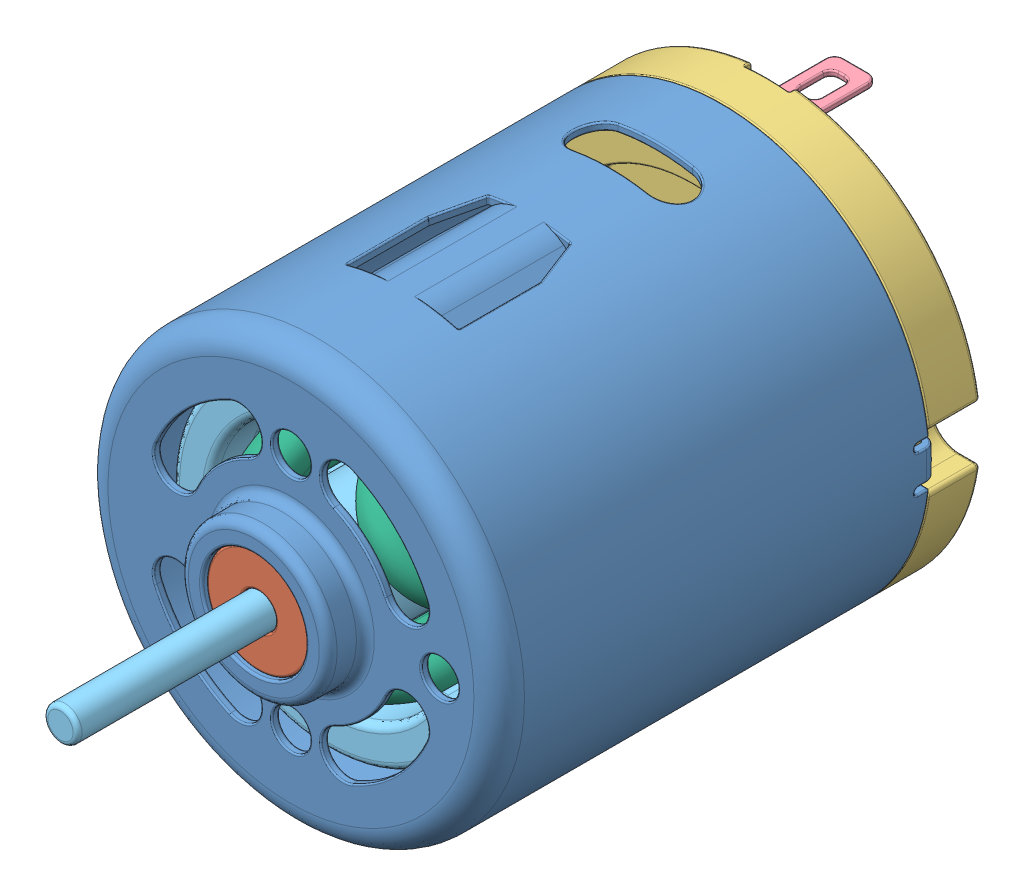
SolidWorks assembly DC Motor 12V, configuration Predeterminado. Lengths in mm.
Overall size (28.03 28 53.5).
9 component instances, 6 part files, 25 mates.
Components (placement in the parent):
- Carcaça12V-1: Carcaça12V [Predeterminado] at (0 0 24.0663) size (28.03 28 32.04)
- Bucha12V-1: Bucha12V [Predeterminado] at (0 0 26.0163) x (0.994754 0.102295 0) z (0 0 1) size (7 7 0.5)
- Mancal12V-1: Mancal12V [Predeterminado] at (0 0 -2.9337) x (-1 0 0) z (0 0 -1) size (27.69 28 8)
- Terminal12V-1: Terminal12V [Predeterminado] at (0 -11.5 -3.9337) x (1 0 0) z (0 1 0) size (2.9 10 0.4)
- Terminal12V-2: Terminal12V [Predeterminado] at (0 11.5 -3.9337) x (1 0 0) z (0 1 0) size (2.9 10 0.4)
- Eixo12V-1: Eixo12V [Predeterminado] at (0 0 39.5663) x (-0.33009 -0.943949 0) z (0 0 1) size (21 20.89 51)
- Enrolamento12V-1: Enrolamento12V [Predeterminado] at (-5.1702 1.808 12.5663) x (0.33009 0.943949 0) z (0 0 1) size (10 3 20)
- Enrolamento12V-2: Enrolamento12V [Predeterminado] at (1.0194 -5.3815 12.5663) x (-0.982529 -0.186108 0) z (0 0 1) size (10 3 20)
- Enrolamento12V-3: Enrolamento12V [Predeterminado] at (4.1509 3.5736 12.5663) x (0.652439 -0.757841 0) z (0 0 1) size (10 3 20)
Mates (geometry in assembly coordinates):
- Concentric1: concentric: cylinder of Carcaça12V-1 through (0 0 -4.9337) axis (0 0 1) radius 14; cylinder of Eixo12V-1 through (0 0 -11.4337) axis (0 0 1) radius 1.15
- Coincident1: coincident: plane of Carcaça12V-1 through (0 0 23.5663) normal (0 0 -1); plane of Eixo12V-1 through (0 0 23.5663) normal (0 0 1)
- Concentric2: concentric: cylinder of Carcaça12V-1 through (0 0 -4.9337) axis (0 0 1) radius 14; cylinder of Bucha12V-1 through (0 0 26.2663) axis (0 0 -1) radius 1.15
- Distance1: distance = 0.3 mm: plane of Carcaça12V-1 through (0 0 26.5663) normal (0 0 1); plane of Bucha12V-1 through (0 0 26.2663) normal (0 0 1)
- Concentric3: concentric: cylinder of Carcaça12V-1 through (0 0 -4.9337) axis (0 0 1) radius 14; cylinder of Mancal12V-1 through (0 0 -8.4337) axis (0 0 1) radius 14
- Coincident2: coincident: plane of Carcaça12V-1 through (0 0 -4.9337) normal (0 0 -1); plane of Mancal12V-1 through (0 14 -4.9337) normal (0 0 1)
- Coincident3: coincident: plane of Carcaça12V-1 through (0 0 24.0663) normal (0 1 0); plane of Mancal12V-1 through (0 0 -2.9337) normal (0 1 0)
- Coincident4: coincident: plane of Terminal12V-1 through (-1.45 -11.3 -3.9337) normal (0 0 1); plane of Terminal12V-2 through (-1.45 11.7 -3.9337) normal (0 0 1)
- Coincident5: coincident: plane of Terminal12V-1 through (0 -11.5 -3.9337) normal (1 0 0); plane of Terminal12V-2 through (0 11.5 -3.9337) normal (1 0 0)
- Coincident6: coincident: plane of Carcaça12V-1 through (0 0 24.0663) normal (1 0 0); plane of Terminal12V-1 through (0 -11.5 -3.9337) normal (1 0 0)
- Parallel1: parallel: plane of Carcaça12V-1 through (0 0 24.0663) normal (0 1 0); plane of Terminal12V-1 through (0 -11.5 -3.9337) normal (0 1 0)
- Distance2: distance = 5.5 mm: plane of Mancal12V-1 through (0 0 -8.4337) normal (0 0 -1); plane of Terminal12V-2 through (-1.45 11.7 -13.9337) normal (0 0 -1)
- Coincident10: coincident: plane of Mancal12V-1 through (1.5 11.7 -2.9337) normal (0 -1 0); plane of Terminal12V-2 through (-1.45 11.7 -3.9337) normal (0 1 0)
- Coincident11: coincident: plane of Mancal12V-1 through (1.5 -11.7 -2.9337) normal (0 1 0); plane of Terminal12V-1 through (-1.45 -11.7 -3.9337) normal (0 -1 0)
- Coincident12: coincident: plane of Carcaça12V-1 through (0 0 24.0663) normal (1 0 0); plane of assembly through (0 0 0) normal (1 0 0)
- Coincident13: coincident: plane of Carcaça12V-1 through (0 0 24.0663) normal (0 1 0); plane of assembly through (0 0 0) normal (0 1 0)
- Coincident14: coincident: plane of Eixo12V-1 through (-7.8225 1.6761 -11.4337) normal (-0.33009 -0.943949 0); plane of Enrolamento12V-1 through (-6.9162 1.3592 6.5663) normal (0.33009 0.943949 0)
- Coincident15: coincident: plane of Eixo12V-1 through (0 0 18.5663) normal (0 0 1); plane of Enrolamento12V-1 through (-6.9162 1.3592 18.5663) normal (0 0 -1)
- Tangent1: tangent: cylinder of Eixo12V-1 through (0 0 -11.4337) axis (0 0 1) radius 8; face of Enrolamento12V-1
- Concentric4: concentric: circle of ?; circle of ?
- Coincident19: coincident: plane of ? through (-3.4941 13.04 22.3663) normal (0 0 1); plane of ? through (3.4941 13.04 22.3663) normal (0 0 1)
- Concentric5: concentric: circle of Carcaça12V-1; circle of ?
- Coincident20: coincident: plane of ?; plane of ?
- Coincident21: coincident: plane of assembly through (0 0 24.0663) normal (0 1 0)
- Coincident22: coincident: circle of Carcaça12V-1; plane of ? through (-3.4941 13.04 22.3663) normal (0 0 1)
